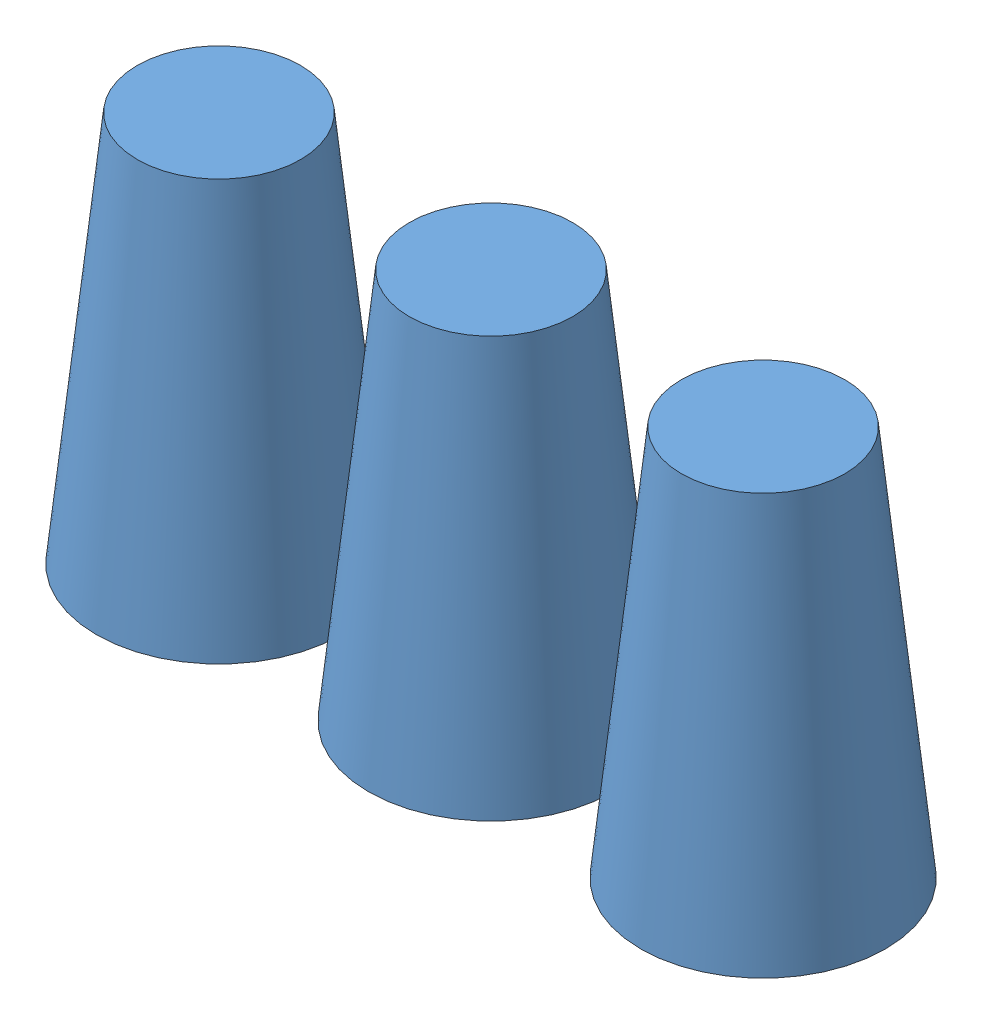
SolidWorks assembly Assem1, configuration Default. Lengths in mm.
Overall size (232 115 72).
3 component instances, 1 part files, 0 mates.
Components (placement in the parent):
- Eurobot2020_Glass-1: Eurobot2020_Glass [Default] at (-6.8995 8.7804 110.307) size (72 115 72)
- Eurobot2020_Glass-2: Eurobot2020_Glass [Default] at (73.1005 8.7804 110.307) size (72 115 72)
- Eurobot2020_Glass-3: Eurobot2020_Glass [Default] at (153.1005 8.7804 110.307) size (72 115 72)
